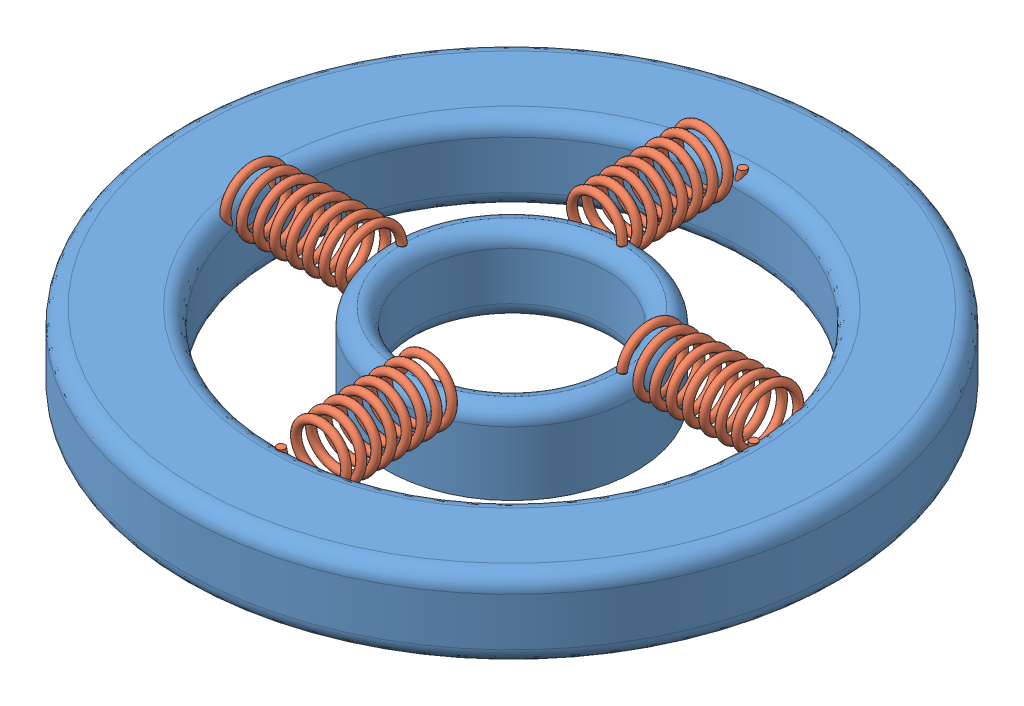
SolidWorks assembly Belt-Final, configuration Default. Lengths in mm.
Overall size (835.13 140.9 835.13).
5 component instances, 2 part files, 0 mates.
Components (placement in the parent):
- Belt-NoSprings-1: Belt-NoSprings [Default] at (85.999 140.6575 223.9845) size (835.13 101.18 835.13)
- Spring-1: Spring [Default] at (383.9244 241.5588 182.109) x (0 -1 0) z (-0.043176 0 -0.999067) size (80 180 80)
- Spring-2: Spring [Default] at (44.1235 241.5588 -73.9408) x (0 -1 0) z (-0.999067 0 0.043176) size (80 180 80)
- Spring-3: Spring [Default] at (-211.9263 241.5588 265.8601) x (0 -1 0) z (0.043176 0 0.999067) size (80 180 80)
- Spring-4: Spring [Default] at (127.8745 241.5588 521.9099) x (0 -1 0) z (0.999067 0 -0.043176) size (80 180 80)
